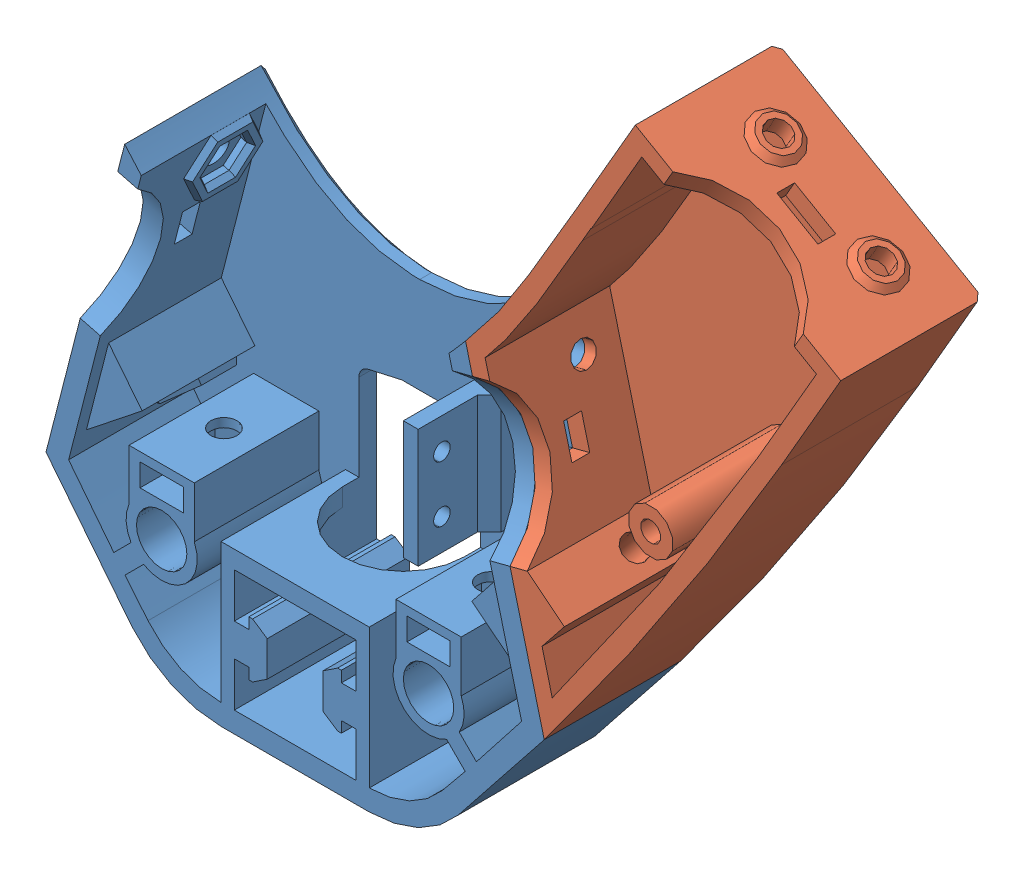
SolidWorks assembly Bottom Triangle Assembly, configuration Default. Lengths in mm.
Overall size (216 130.25 60.11).
8 component instances, 8 part files, 10 mates.
Components (placement in the parent):
- 3DR Bottom Motor Mount-1: 3DR Bottom Motor Mount [Simple Center] at origin size (84 76.99 60.11)
- Wings-1: Wings [Longer with Nut] at (42.1437 10.9951 0) x (0.968477 0.249105 0) z (0 0 1) size (67.81 90.53 27.11)
- MirrorWings-2: MirrorWings [Default] at (-42.1437 10.9951 0) x (-0.968477 0.249105 0) z (0 0 -1) (suppressed, hidden)
- MirrorWings1-2: MirrorWings1 [Top With Dimples] at (-42.1437 10.9951 0) x (-0.968477 0.249105 0) z (0 0 -1) (suppressed, hidden)
- Microswitch-1: Microswitch [Default] at (12 33.25 15) x (0 1 0) z (1 0 0) (suppressed, hidden)
- Cap Head Screw-1: Cap Head Screw [M4 x 10] at (22.5 12.7724 13.5) x (0.845486 0 0.533998) z (0 1 0) (suppressed, hidden)
- Wing Mirror Long-1: Wing Mirror Long [Longer With Dimple] at (-134.6068 171.146 0) x (-0.268507 -0.963278 0) z (0 0 1) size (89.72 68.95 27.11)
- Wing Mirror Long Top-1: Wing Mirror Long Top [Longer Top With Dimples] at (-134.6068 171.146 0) x (-0.268507 -0.963278 0) z (0 0 1) (suppressed, hidden)
Mates (geometry in assembly coordinates):
- Coincident1: coincident aligned: plane of 3DR Bottom Motor Mount-1 through (-12.5 -13.75 0) normal (0 0 -1); plane of Wings-1 through (-409.8106 355.6043 0) normal (0 0 -1)
- Coincident2: coincident anti-aligned: plane of 3DR Bottom Motor Mount-1 through (28.7322 63.1367 60) normal (0.968477 0.249105 0); plane of Wings-1 through (28.7322 63.1367 3) normal (-0.968477 -0.249105 0)
- Coincident3: coincident anti-aligned: plane of 3DR Bottom Motor Mount-1 through (15.25 41.25 17) normal (-1 0 0); plane of Microswitch-1 through (15.25 21.25 11) normal (1 0 0)
- Concentric1: concentric anti-aligned: cylinder of 3DR Bottom Motor Mount-1 through (42.001 28.5 17) axis (-1 0 0) radius 1.4; cylinder of Microswitch-1 through (8.75 26.5 13) axis (1 0 0) radius 1.25
- Concentric2: concentric anti-aligned: cylinder of 3DR Bottom Motor Mount-1 through (42.001 38 17) axis (-1 0 0) radius 1.4; cylinder of Microswitch-1 through (8.75 36 13) axis (1 0 0) radius 1.25
- Concentric3: concentric anti-aligned: cylinder of 3DR Bottom Motor Mount-1 through (22.5 -13.751 10.5) axis (0 1 0) radius 2.2; cylinder of Cap Head Screw-1 through (22.5 22.7724 10.5) axis (0 -1 0) radius 1.96
- Concentric6: concentric anti-aligned: cylinder of 3DR Bottom Motor Mount-1 through (-57.2131 51.0508 9) axis (0.622037 -0.782988 0) radius 2.1; cylinder of Wing Mirror Long-1 through (-32.0898 19.4268 9) axis (-0.622037 0.782988 0) radius 2.1
- Coincident4: coincident anti-aligned: plane of 3DR Bottom Motor Mount-1 through (-28.7322 63.1367 60) normal (-0.968477 0.249105 0); plane of Wing Mirror Long-1 through (-28.7322 63.1367 3) normal (0.968477 -0.249105 0)
- Concentric7: concentric anti-aligned: cylinder of 3DR Bottom Motor Mount-1 through (-57.2131 51.0508 9) axis (0.622037 -0.782988 0) radius 2.1; cylinder of Wing Mirror Long Top-1 through (-32.0898 19.4268 9) axis (-0.622037 0.782988 0) radius 2.1
- Concentric8: concentric aligned: cylinder of 3DR Bottom Motor Mount-1 through (-21.0403 52.8979 9) axis (-0.968477 0.249105 0) radius 2.1; cylinder of Wing Mirror Long Top-1 through (-23.9457 53.6452 9) axis (-0.968477 0.249105 0) radius 2.1
